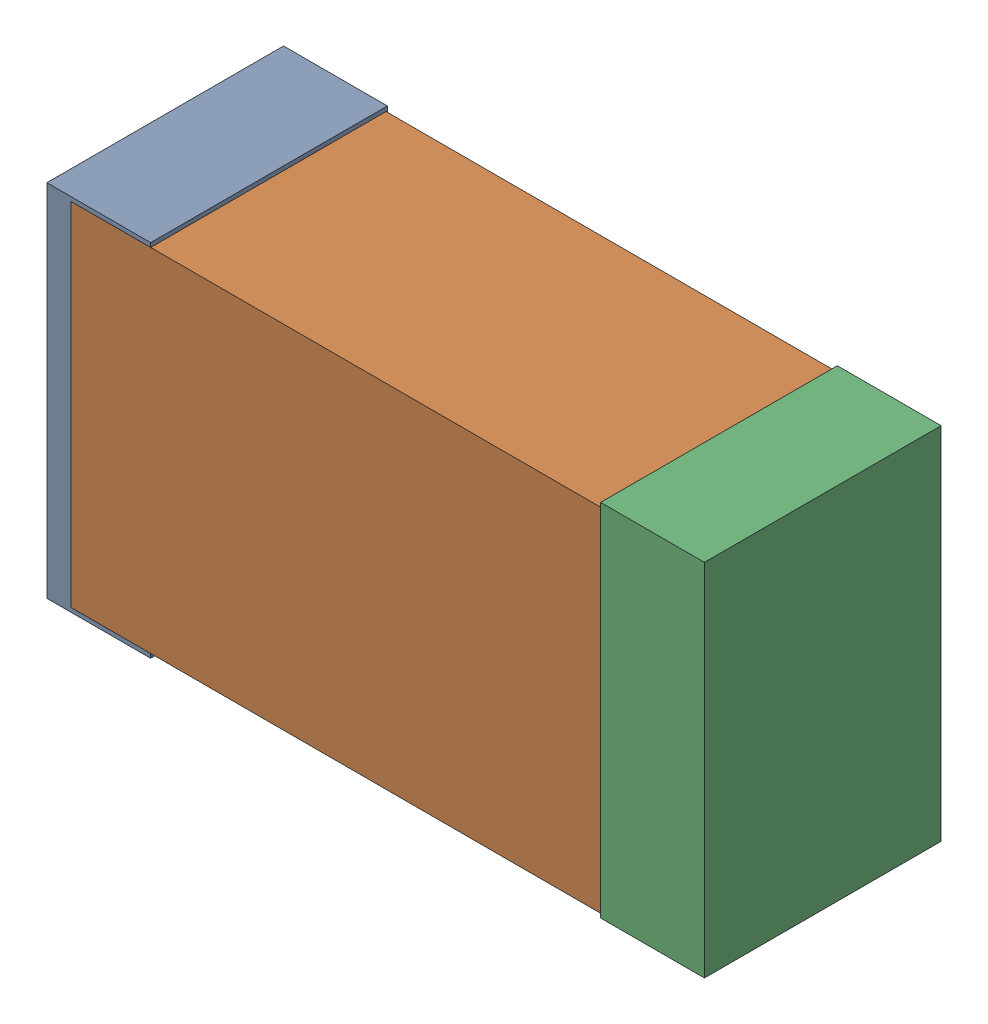
SolidWorks assembly USB01_C10, configuration Default. Lengths in mm.
Overall size (2.38 1.3 0.85).
6 component instances, 2 part files, 0 mates.
Components (placement in the parent):
- 384311232-1: 384311232 [Default] at (172.99 75.565 -1.9574) size (0.38 1.3 0.85)
  - Extruded_8-1: Extruded_8 [Default] at origin size (0.38 1.3 0.85)
- 384311360-1: 384311360 [Default] at (173.99 75.565 -1.9524) size (2.2 1.27 0.85)
  - Extruded_9-1: Extruded_9 [Default] at origin size (2.2 1.27 0.85)
- 384311232-2: 384311232 [Default] at (174.99 75.565 -1.9574) size (0.38 1.3 0.85)
  - Extruded_8-1: Extruded_8 [Default] at origin size (0.38 1.3 0.85)
